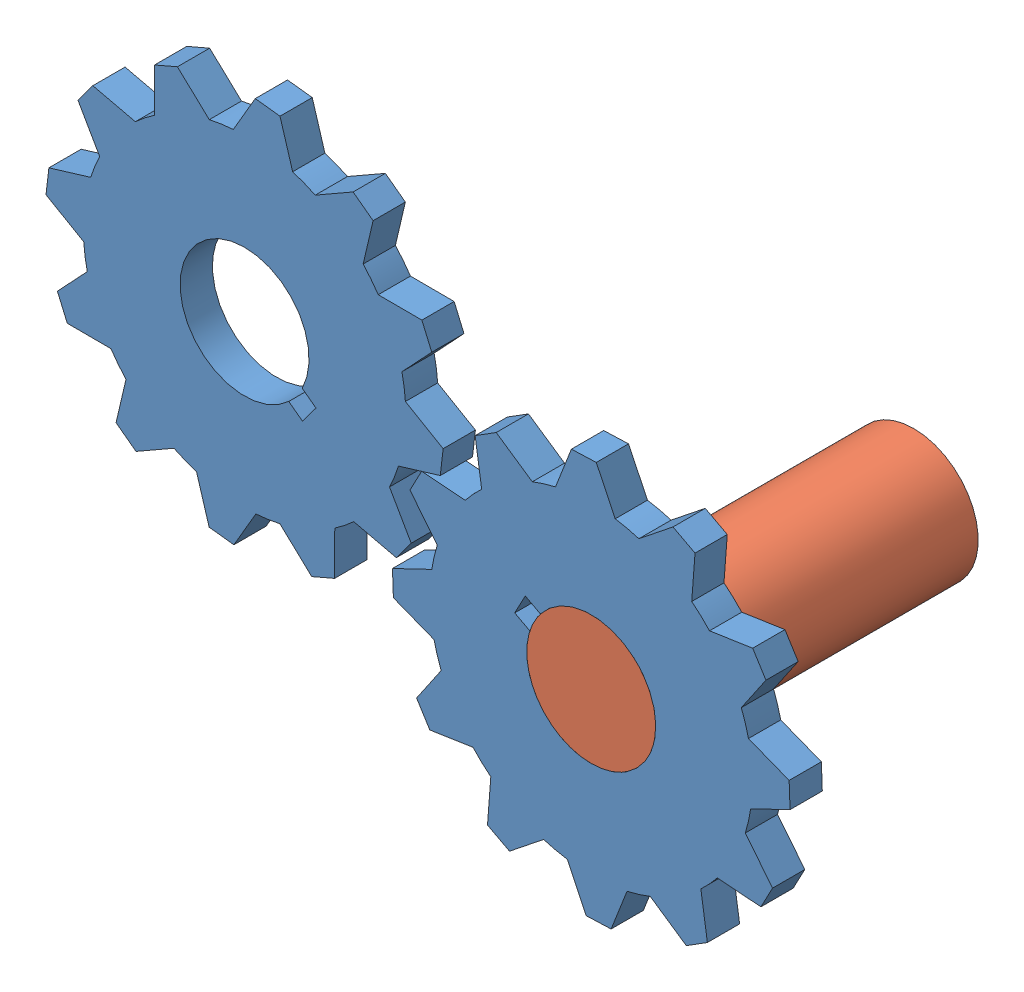
SolidWorks assembly Test_4_2, configuration Default. Lengths in mm.
Overall size (276.82 214.23 100).
3 component instances, 2 part files, 5 mates.
Components (placement in the parent):
- Gear_1-3: Gear_1 [Default] at (-105.6577 26.5914 -10) x (-0.467314 -0.884091 0) z (0 0 1) size (123.1 123.1 10)
- Gear_1-4: Gear_1 [Default] at (-213.1724 71.5073 -10) x (0.597211 0.802084 0) z (0 0 1) size (123.1 123.1 10)
- Cilinder-1: Cilinder [Default] at (-146.9212 43.7493 -100) x (-0.996906 -0.078602 0) z (0 0 1) size (40 40 100)
Mates (geometry in assembly coordinates):
- Coincident1: coincident: plane of assembly through (0 0 0) normal (0 0 1); plane of Gear_1-4 through (-213.1724 71.5073 0) normal (0 0 1); plane of assembly
- Coincident2: coincident: plane of assembly through (0 0 0) normal (0 0 1); plane of Gear_1-3 through (-105.6577 26.5914 0) normal (0 0 1); plane of assembly
- Concentric1: concentric: circle of assembly; circle of Gear_1-4; circle of assembly
- Concentric2: concentric: circle of assembly; circle of Gear_1-3; circle of assembly
- Coincident3: coincident: circle of Gear_1-3; circle of Cilinder-1
